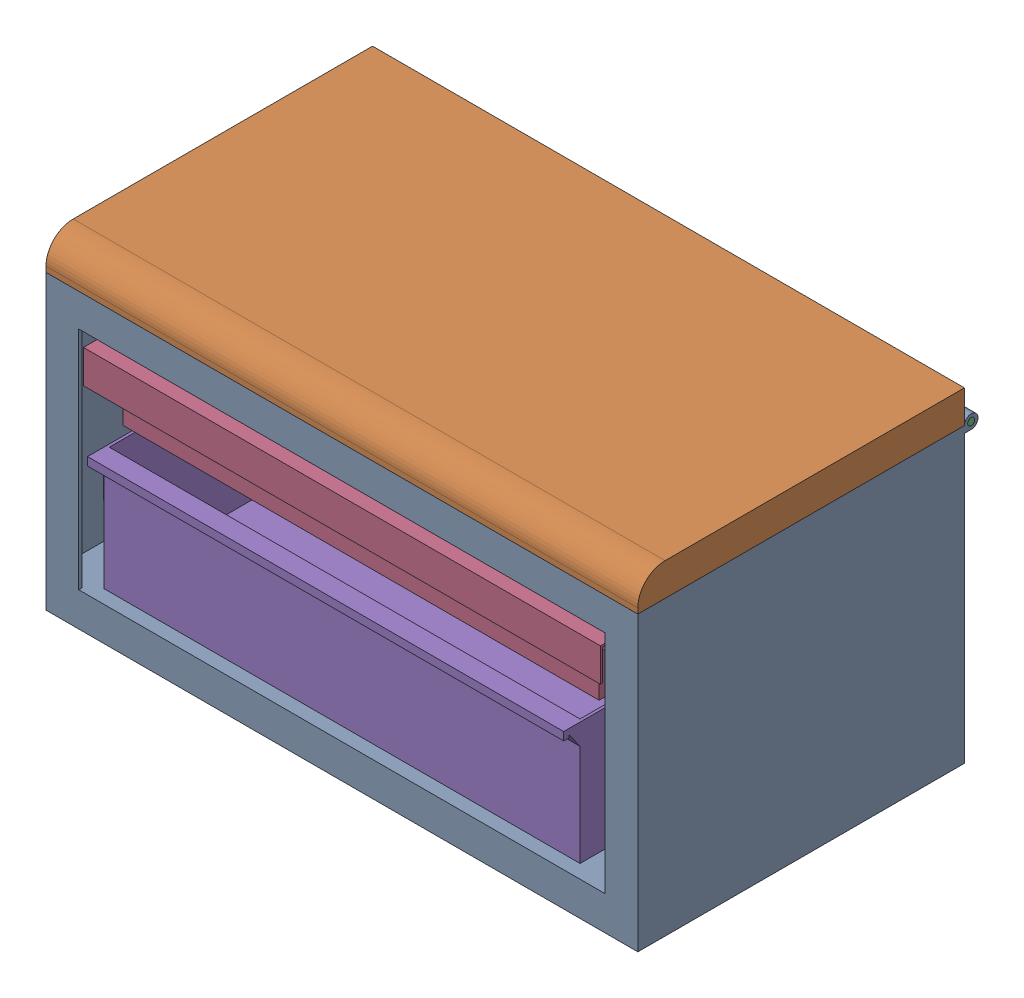
SolidWorks assembly SP-A0101-AA-Tool Box, configuration Default. Lengths in mm.
Overall size (276.23 151.77 166.37).
5 component instances, 5 part files, 11 mates.
Components (placement in the parent):
- SP-00001-AA-Box-1: SP-00001-AA-Box [Default] at (-32.56 103.5596 146.5347) size (276.23 139.7 158.75)
- SP-00002-AA-Lid-1: SP-00002-AA-Lid [Default] at (-32.56 103.5596 146.5347) size (276.23 18.41 158.75)
- SP-00005-AA-Hinge Pin-1: SP-00005-AA-Hinge Pin [Default] at (-34.084 103.5596 -7.5163) size (276.23 3.3 3.3)
- SP-00003-AA-Upper Drawer-1: SP-00003-AA-Upper Drawer [Default] at (104.0285 50.7911 139.1687) size (241.3 31.18 135.89)
- SP-00004-AA-lower drawer-1: SP-00004-AA-lower drawer [Default] at (104.0285 -10.7404 84.5587) size (222.25 57.15 134.62)
Mates (geometry in assembly coordinates):
- Coincident1: coincident aligned: plane of SP-00001-AA-Box-1 through (242.141 -32.9654 148.0587) normal (1 0 0); plane of SP-00002-AA-Lid-1 through (242.141 118.7996 146.5347) normal (1 0 0)
- Concentric1: concentric anti-aligned: cylinder of SP-00001-AA-Box-1 through (159.591 103.5596 -7.5163) axis (1 0 0) radius 1.651; cylinder of SP-00005-AA-Hinge Pin-1 through (242.141 103.5596 -7.5163) axis (-1 0 0) radius 1.651
- Concentric2: concentric aligned: cylinder of SP-00002-AA-Lid-1 through (154.8285 103.5596 -7.5163) axis (-1 0 0) radius 1.651; cylinder of SP-00005-AA-Hinge Pin-1 through (242.141 103.5596 -7.5163) axis (-1 0 0) radius 1.651
- Coincident2: coincident aligned: plane of SP-00001-AA-Box-1 through (-34.084 -32.9654 148.0587) normal (-1 0 0); plane of SP-00005-AA-Hinge Pin-1 through (-34.084 103.5596 -7.5163) normal (-1 0 0)
- LimitAngle1: limit planar angle = 0 rad anti-aligned: plane of SP-00002-AA-Lid-1 through (-32.56 103.5596 146.5347) normal (0 -1 0); plane of SP-00001-AA-Box-1 through (-32.56 103.5596 146.5347) normal (0 1 0)
- Coincident4: coincident anti-aligned: plane of SP-00001-AA-Box-1 through (215.1535 69.2696 179.8596) normal (-1 0 0); plane of SP-00003-AA-Upper Drawer-1 through (215.1535 53.3311 139.1687) normal (1 0 0)
- Distance3: distance = 6.35 mm anti-aligned: plane of SP-00001-AA-Box-1 through (-32.56 88.3196 146.5347) normal (0 -1 0); plane of SP-00003-AA-Upper Drawer-1 through (-16.6215 81.9696 139.1687) normal (0 1 0)
- LimitDistance1: limit distance = 0 mm aligned: plane of SP-00003-AA-Upper Drawer-1 through (-16.6215 81.9696 148.0587) normal (0 0 1); plane of SP-00001-AA-Box-1 through (-34.084 -32.9654 148.0587) normal (0 0 1)
- Coincident7: coincident anti-aligned: plane of SP-00001-AA-Box-1 through (215.1535 18.4696 179.8596) normal (-1 0 0); plane of SP-00004-AA-lower drawer-1 through (215.1535 46.4096 148.0587) normal (1 0 0)
- Distance4: distance = 6.35 mm anti-aligned: plane of SP-00001-AA-Box-1 through (-32.56 -17.0904 146.5347) normal (0 1 0); plane of SP-00004-AA-lower drawer-1 through (104.0285 -10.7404 84.5587) normal (0 -1 0)
- LimitDistance2: limit distance = 0 mm aligned: plane of SP-00001-AA-Box-1 through (-34.084 -32.9654 148.0587) normal (0 0 1); plane of SP-00004-AA-lower drawer-1 through (215.1535 46.4096 148.0587) normal (0 0 1)
